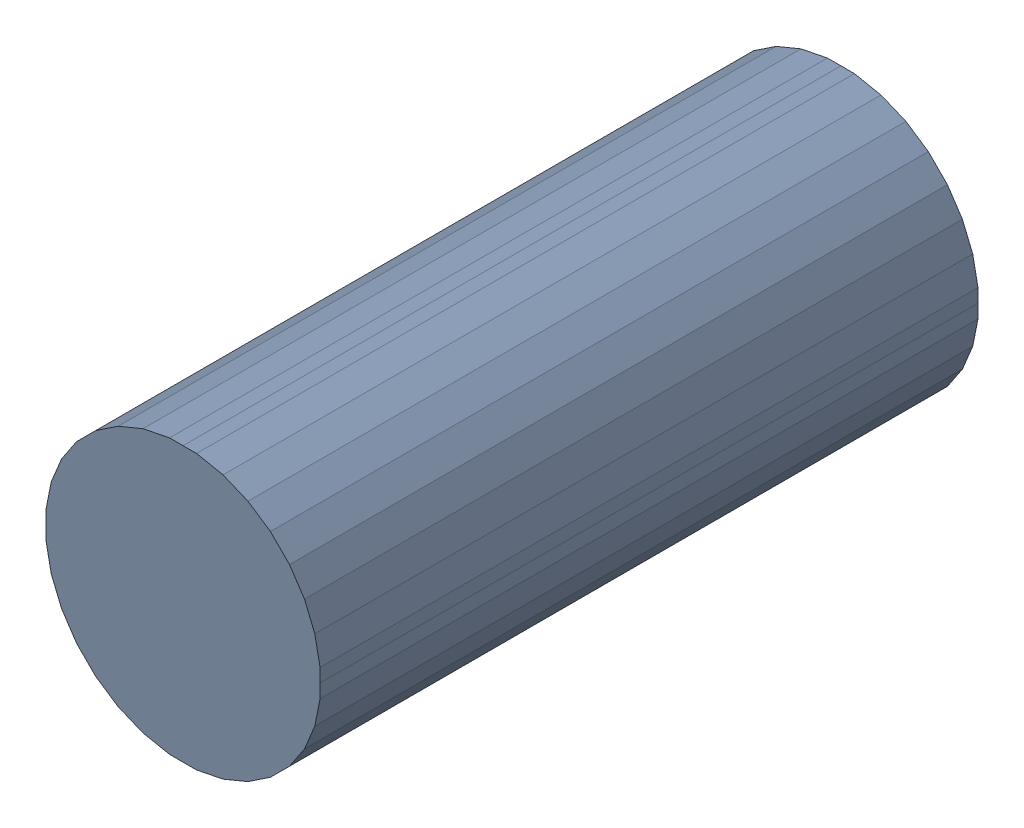
SolidWorks assembly C4.step, configuration Default. Lengths in mm.
Overall size (5 5 12).
2 component instances, 1 part files, 0 mates.
Components (placement in the parent):
- 6100339584.step-1: 6100339584.step [Default] at (36.576 35.941 0) size (5 5 12)
  - Extruded-49.step-1: Extruded-49.step [Default] at origin size (5 5 12)
